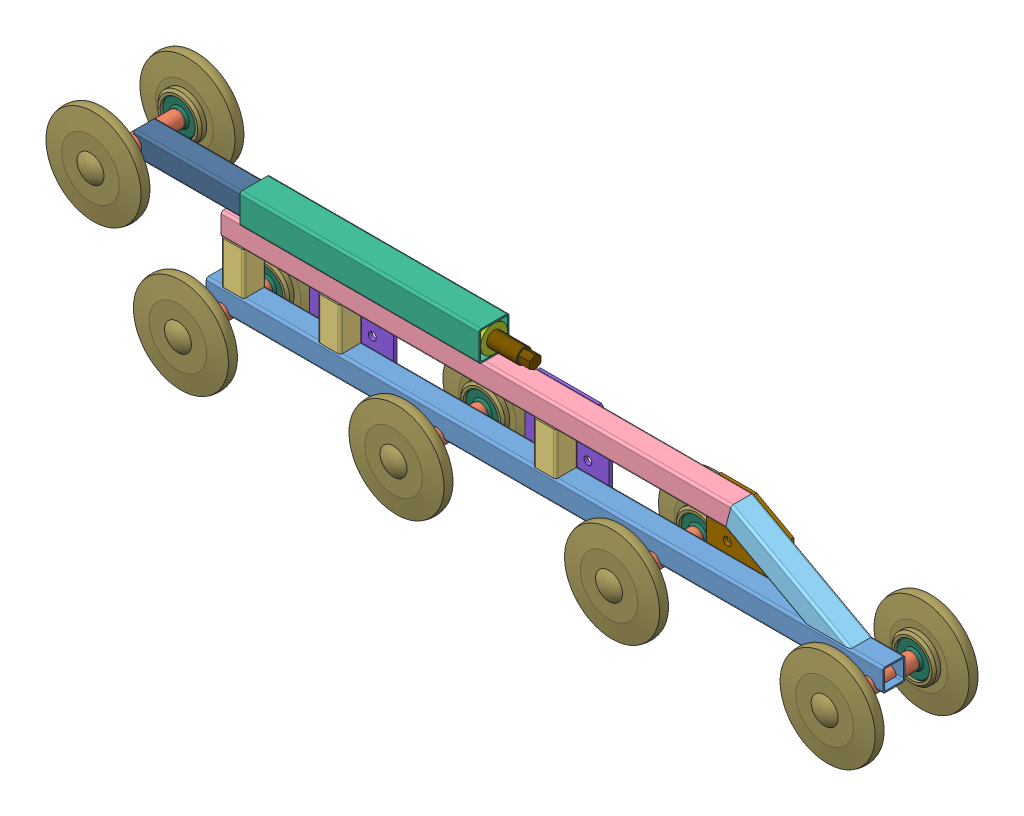
SolidWorks assembly ТП.016.02.00 - Гусеничный модуль в сборе, configuration Левый. Lengths in mm.
Overall size (1147.02 302.71 157.68).
97 component instances, 18 part files, 54 mates.
Components (placement in the parent):
- ТП.016.02.01.00 - Модуль гусеницы силовой-1: ТП.016.02.01.00 - Модуль гусеницы силовой [Левый] at origin size (904.98 176.07 133.68)
  - ТП.016.02.01.01.00 - Рама гусеницы с осями-1: ТП.016.02.01.01.00 - Рама гусеницы с осями [00] at origin size (904.98 176.07 133.68)
    - ТП.016.02.01.01.01 - Нижняя балка гуленицы (30х30)-1: ТП.016.02.01.01.01 - Нижняя балка гуленицы (30х30) [--] at origin size (904.98 30 30)
    - ТП.016.02.01.01.02(02) - Ось цельная 21_3мм-1: ТП.016.02.01.01.02(02) - Ось цельная 21_3мм [--] x (0 0 1) z (-1 0 0) size (133.68 21.3 21.3)
    - ТП.016.02.01.01.02(02) - Ось цельная 21_3мм-2: ТП.016.02.01.01.02(02) - Ось цельная 21_3мм [--] at (288.3267 0 0) x (0 0 1) z (-0.987351 0.158553 0) size (133.68 21.3 21.3)
    - ТП.016.02.01.01.02(02) - Ось цельная 21_3мм-3: ТП.016.02.01.01.02(02) - Ось цельная 21_3мм [--] at (576.6534 0 0) x (0 0 1) z (-0.959125 0.282984 0) size (133.68 21.3 21.3)
    - ТП.016.02.01.01.02(02) - Ось цельная 21_3мм-4: ТП.016.02.01.01.02(02) - Ось цельная 21_3мм [--] at (864.9801 0 0) x (0 0 1) z (-0.928571 0.371154 0) size (133.68 21.3 21.3)
    - ТП.016.02.01.01.03 - Связка балок гусеничного модуля-1: ТП.016.02.01.01.03 - Связка балок гусеничного модуля [--] at (0 86.7738 0) x (-1 0 0) z (0 0 -1) size (30 56.77 30)
    - ТП.016.02.01.01.03 - Связка балок гусеничного модуля-2: ТП.016.02.01.01.03 - Связка балок гусеничного модуля [--] at (129.1634 86.7738 0) x (-1 0 0) z (0 0 -1) size (30 56.77 30)
    - ТП.016.02.01.01.03 - Связка балок гусеничного модуля-3: ТП.016.02.01.01.03 - Связка балок гусеничного модуля [--] at (417.4901 86.7738 0) x (-1 0 0) z (0 0 -1) size (30 56.77 30)
    - ТП.016.02.01.01.04 - Верхняя балка рамы гусеницы-1: ТП.016.02.01.01.04 - Верхняя балка рамы гусеницы [--] at (0 136.7738 0) x (0 0 1) z (-1 0 0) size (30 129.94 872.16)
    - ТП.016.02.01.01.05 - Задняя косая-1: ТП.016.02.01.01.05 - Задняя косая [--] at (864.9801 0 -15) x (0 0 -1) z (0.877984 -0.478691 0) size (30 30 181.27)
    - ТП.016.02.01.01.06.00 - Стакан натяжителя-1: ТП.016.02.01.01.06.00 - Стакан натяжителя [00] at (30 136.7738 0) x (-1 0 0) z (0 0 -1) size (320 50.91 50.91)
      - ТП.016.02.01.01.06.01 - Рубашка штока ролика натяжного-1: ТП.016.02.01.01.06.01 - Рубашка штока ролика натяжного [--] at origin size (320 40 40)
      - ТП.016.02.01.01.06.02 - Гайка рубашки штока-1: ТП.016.02.01.01.06.02 - Гайка рубашки штока [--] at (-320 0 0) x (0 -0.713098 -0.701064) z (1 0 0) size (36 36 20)
  - ТП.016.01.01.01.01.02 - Пластина кронштейна (5мм)-1: ТП.016.01.01.01.01.02 - Пластина кронштейна (5мм) [--] at (144.1634 0 20) size (112 110.77 5) (hidden)
  - ТП.016.01.01.01.01.02 - Пластина кронштейна (5мм)-2: ТП.016.01.01.01.01.02 - Пластина кронштейна (5мм) [--] at (432.4901 0 20) size (112 110.77 5) (hidden)
  - ТП.016.01.01.01.01.05 - Пластина кронштейна задняя (5мм)-1: ТП.016.01.01.01.01.05 - Пластина кронштейна задняя (5мм) [--] at (674.9034 0 15) x (-1 0 0) z (0 0 -1) size (112 110.77 5) (hidden)
  - ТП.016.01.01.01.01.02 - Пластина кронштейна (5мм)-4: ТП.016.01.01.01.01.02 - Пластина кронштейна (5мм) [--] at (144.1634 0 -20) x (-1 0 0) z (0 0 -1) size (112 110.77 5)
  - ТП.016.01.01.01.01.02 - Пластина кронштейна (5мм)-6: ТП.016.01.01.01.01.02 - Пластина кронштейна (5мм) [--] at (432.4901 0 -20) x (-1 0 0) z (0 0 -1) size (112 110.77 5)
  - ТП.016.01.01.01.01.05 - Пластина кронштейна задняя (5мм)-2: ТП.016.01.01.01.01.05 - Пластина кронштейна задняя (5мм) [--] at (674.9034 0 -20) x (-1 0 0) z (0 0 -1) size (112 110.77 5)
- ТП.016.02.02.00 - Натяжитель гусеницы-1: ТП.016.02.02.00 - Натяжитель гусеницы [00] at (-117 136.7738 0) x (-1 0 0) z (0 0 1) size (371.74 149.44 157.68)
  - ТП.016.02.02.01.00 - Толкатель натяжки-1: ТП.016.02.02.01.00 - Толкатель натяжки [00] at origin size (311.12 30 133.68)
    - ТП.016.02.02.01.01 - Шток натяжного ролика (30х30)-1: ТП.016.02.02.01.01 - Шток натяжного ролика (30х30) [--] at origin size (297.02 30 30)
    - ТП.016.02.01.01.02(02) - Ось цельная 21_3мм-1: ТП.016.02.01.01.02(02) - Ось цельная 21_3мм [--] x (0 0 1) z (-0.910058 0.41448 0) size (133.68 21.3 21.3)
    - ТП.016.02.02.01.02 - Заглушка штока-1: ТП.016.02.02.01.02 - Заглушка штока [--] at (-297.0168 0 0) x (0 -1 0) z (1 0 0) size (26 26 20)
  - Каток 129(47) в сборе-1: Каток 129(47) в сборе [00] at (0 0 62.8416) x (0 0 1) z (1 0 0) size (35.7 129 129)
    - Каток 129(47)-1: Каток 129(47) [--] at origin size (35 129 129)
    - Подшипник ГОСТ 8338-75 -1: Подшипник ГОСТ 8338-75  [Подшипник 204 ГОСТ 8338-75] at (-1 0 0) x (1 0 0) z (0 -0.327433 -0.944874) size (14 47 47)
    - Стопор внутренний до 165мм (ГОСТ 13943-86)-1: Стопор внутренний до 165мм (ГОСТ 13943-86) [Кольцо 47] at (-8 0 0) x (0 0.910839 0.412761) z (-1 0 0) size (49.5 51.2 1.7)
    - Сальник 47х20-1: Сальник 47х20 [--] at (-9.7 0 0) x (-1 0 0) z (0 0.937697 -0.347453) size (10 47 47)
  - Каток 129(47) в сборе-2: Каток 129(47) в сборе [00] at (0 0 -62.8416) x (0 0 -1) z (-0.173648 0.984808 0) size (35.7 129 129)
    - Каток 129(47)-1: Каток 129(47) [--] at origin size (35 129 129)
    - Подшипник ГОСТ 8338-75 -1: Подшипник ГОСТ 8338-75  [Подшипник 204 ГОСТ 8338-75] at (-1 0 0) x (1 0 0) z (0 -0.327433 -0.944874) size (14 47 47)
    - Стопор внутренний до 165мм (ГОСТ 13943-86)-1: Стопор внутренний до 165мм (ГОСТ 13943-86) [Кольцо 47] at (-8 0 0) x (0 0.910839 0.412761) z (-1 0 0) size (49.5 51.2 1.7)
    - Сальник 47х20-1: Сальник 47х20 [--] at (-9.7 0 0) x (-1 0 0) z (0 0.937697 -0.347453) size (10 47 47)
  - ТП.016.02.02.02 - Шайба оси-1: ТП.016.02.02.02 - Шайба оси [--] at (0 0 -66.3614) x (0 0 1) z (0.48394 0.875101 0) size (4 24 24)
  - Болты с шестигранной головкой кт.В (ГОСТ 7798-70)-1: Болты с шестигранной головкой кт.В (ГОСТ 7798-70) [Болт М6-6gx14(S10) ГОСТ 7798-77] at (0 0 -69.3416) x (0 0 1) z (0.143998 -0.989578 0) size (18 10.9 10)
  - ТП.016.02.02.02 - Шайба оси-2: ТП.016.02.02.02 - Шайба оси [--] at (0 0 66.3614) x (0 0 -1) z (0.777771 0.628548 0) size (4 24 24)
  - Болты с шестигранной головкой кт.В (ГОСТ 7798-70)-2: Болты с шестигранной головкой кт.В (ГОСТ 7798-70) [Болт М6-6gx14(S10) ГОСТ 7798-77] at (0 0 69.3416) x (0 0 -1) z (-0.999549 -0.030028 0) size (18 10.9 10)
- ТП.016.02.03 - Винт натяжителя-1: ТП.016.02.03 - Винт натяжителя [--] at (350.0168 136.7738 0) x (0 -0.01927 -0.999814) z (-1 0 0) size (20 20 231.35)
- Каток 129(47) в сборе-1: Каток 129(47) в сборе [00] at (0 0 -62.8416) x (0 0 -1) z (-0.261474 0.96521 0) size (35.7 129 129)
  - Каток 129(47)-1: Каток 129(47) [--] at origin size (35 129 129)
  - Подшипник ГОСТ 8338-75 -1: Подшипник ГОСТ 8338-75  [Подшипник 204 ГОСТ 8338-75] at (-1 0 0) x (1 0 0) z (0 -0.327433 -0.944874) size (14 47 47)
  - Стопор внутренний до 165мм (ГОСТ 13943-86)-1: Стопор внутренний до 165мм (ГОСТ 13943-86) [Кольцо 47] at (-8 0 0) x (0 0.910839 0.412761) z (-1 0 0) size (49.5 51.2 1.7)
  - Сальник 47х20-1: Сальник 47х20 [--] at (-9.7 0 0) x (-1 0 0) z (0 0.937697 -0.347453) size (10 47 47)
- Каток 129(47) в сборе-2: Каток 129(47) в сборе [00] at (288.3267 0 -62.8416) x (0 0 -1) z (-0.411203 0.911544 0) size (35.7 129 129)
  - Каток 129(47)-1: Каток 129(47) [--] at origin size (35 129 129)
  - Подшипник ГОСТ 8338-75 -1: Подшипник ГОСТ 8338-75  [Подшипник 204 ГОСТ 8338-75] at (-1 0 0) x (1 0 0) z (0 -0.327433 -0.944874) size (14 47 47)
  - Стопор внутренний до 165мм (ГОСТ 13943-86)-1: Стопор внутренний до 165мм (ГОСТ 13943-86) [Кольцо 47] at (-8 0 0) x (0 0.910839 0.412761) z (-1 0 0) size (49.5 51.2 1.7)
  - Сальник 47х20-1: Сальник 47х20 [--] at (-9.7 0 0) x (-1 0 0) z (0 0.937697 -0.347453) size (10 47 47)
- Каток 129(47) в сборе-4: Каток 129(47) в сборе [00] at (576.6534 0 -62.8416) x (0 0 -1) z (-0.523925 0.851764 0) size (35.7 129 129)
  - Каток 129(47)-1: Каток 129(47) [--] at origin size (35 129 129)
  - Подшипник ГОСТ 8338-75 -1: Подшипник ГОСТ 8338-75  [Подшипник 204 ГОСТ 8338-75] at (-1 0 0) x (1 0 0) z (0 -0.327433 -0.944874) size (14 47 47)
  - Стопор внутренний до 165мм (ГОСТ 13943-86)-1: Стопор внутренний до 165мм (ГОСТ 13943-86) [Кольцо 47] at (-8 0 0) x (0 0.910839 0.412761) z (-1 0 0) size (49.5 51.2 1.7)
  - Сальник 47х20-1: Сальник 47х20 [--] at (-9.7 0 0) x (-1 0 0) z (0 0.937697 -0.347453) size (10 47 47)
- Каток 129(47) в сборе-6: Каток 129(47) в сборе [00] at (864.9801 0 -62.8416) x (0 0 -1) z (0.601039 -0.79922 0) size (35.7 129 129)
  - Каток 129(47)-1: Каток 129(47) [--] at origin size (35 129 129)
  - Подшипник ГОСТ 8338-75 -1: Подшипник ГОСТ 8338-75  [Подшипник 204 ГОСТ 8338-75] at (-1 0 0) x (1 0 0) z (0 -0.327433 -0.944874) size (14 47 47)
  - Стопор внутренний до 165мм (ГОСТ 13943-86)-1: Стопор внутренний до 165мм (ГОСТ 13943-86) [Кольцо 47] at (-8 0 0) x (0 0.910839 0.412761) z (-1 0 0) size (49.5 51.2 1.7)
  - Сальник 47х20-1: Сальник 47х20 [--] at (-9.7 0 0) x (-1 0 0) z (0 0.937697 -0.347453) size (10 47 47)
- Каток 129(47) в сборе-8: Каток 129(47) в сборе [00] at (864.9801 0 62.8416) x (0 0 1) z (0.907466 0.420125 0) size (35.7 129 129)
  - Каток 129(47)-1: Каток 129(47) [--] at origin size (35 129 129)
  - Подшипник ГОСТ 8338-75 -1: Подшипник ГОСТ 8338-75  [Подшипник 204 ГОСТ 8338-75] at (-1 0 0) x (1 0 0) z (0 -0.327433 -0.944874) size (14 47 47)
  - Стопор внутренний до 165мм (ГОСТ 13943-86)-1: Стопор внутренний до 165мм (ГОСТ 13943-86) [Кольцо 47] at (-8 0 0) x (0 0.910839 0.412761) z (-1 0 0) size (49.5 51.2 1.7)
  - Сальник 47х20-1: Сальник 47х20 [--] at (-9.7 0 0) x (-1 0 0) z (0 0.937697 -0.347453) size (10 47 47)
- Каток 129(47) в сборе-10: Каток 129(47) в сборе [00] at (576.6534 0 62.8416) x (0 0 1) z (0.820726 0.571322 0) size (35.7 129 129)
  - Каток 129(47)-1: Каток 129(47) [--] at origin size (35 129 129)
  - Подшипник ГОСТ 8338-75 -1: Подшипник ГОСТ 8338-75  [Подшипник 204 ГОСТ 8338-75] at (-1 0 0) x (1 0 0) z (0 -0.327433 -0.944874) size (14 47 47)
  - Стопор внутренний до 165мм (ГОСТ 13943-86)-1: Стопор внутренний до 165мм (ГОСТ 13943-86) [Кольцо 47] at (-8 0 0) x (0 0.910839 0.412761) z (-1 0 0) size (49.5 51.2 1.7)
  - Сальник 47х20-1: Сальник 47х20 [--] at (-9.7 0 0) x (-1 0 0) z (0 0.937697 -0.347453) size (10 47 47)
- Каток 129(47) в сборе-12: Каток 129(47) в сборе [00] at (288.3267 0 62.8416) x (0 0 1) z (0.709048 0.70516 0) size (35.7 129 129)
  - Каток 129(47)-1: Каток 129(47) [--] at origin size (35 129 129)
  - Подшипник ГОСТ 8338-75 -1: Подшипник ГОСТ 8338-75  [Подшипник 204 ГОСТ 8338-75] at (-1 0 0) x (1 0 0) z (0 -0.327433 -0.944874) size (14 47 47)
  - Стопор внутренний до 165мм (ГОСТ 13943-86)-1: Стопор внутренний до 165мм (ГОСТ 13943-86) [Кольцо 47] at (-8 0 0) x (0 0.910839 0.412761) z (-1 0 0) size (49.5 51.2 1.7)
  - Сальник 47х20-1: Сальник 47х20 [--] at (-9.7 0 0) x (-1 0 0) z (0 0.937697 -0.347453) size (10 47 47)
- Каток 129(47) в сборе-14: Каток 129(47) в сборе [00] at (0 0 62.8416) x (0 0 1) z (0.575827 0.817572 0) size (35.7 129 129)
  - Каток 129(47)-1: Каток 129(47) [--] at origin size (35 129 129)
  - Подшипник ГОСТ 8338-75 -1: Подшипник ГОСТ 8338-75  [Подшипник 204 ГОСТ 8338-75] at (-1 0 0) x (1 0 0) z (0 -0.327433 -0.944874) size (14 47 47)
  - Стопор внутренний до 165мм (ГОСТ 13943-86)-1: Стопор внутренний до 165мм (ГОСТ 13943-86) [Кольцо 47] at (-8 0 0) x (0 0.910839 0.412761) z (-1 0 0) size (49.5 51.2 1.7)
  - Сальник 47х20-1: Сальник 47х20 [--] at (-9.7 0 0) x (-1 0 0) z (0 0.937697 -0.347453) size (10 47 47)
- ТП.016.02.02.02 - Шайба оси-1: ТП.016.02.02.02 - Шайба оси [--] at (0 0 -66.3614) x (0 0 1) z (0.502694 0.864464 0) size (4 24 24)
- Болты с шестигранной головкой кт.В (ГОСТ 7798-70)-1: Болты с шестигранной головкой кт.В (ГОСТ 7798-70) [Болт М6-6gx16(S10) ГОСТ 7798-77] at (0 0 -69.3416) x (0 0 1) z (0.899536 0.436848 0) size (20 10.9 10)
- ТП.016.02.02.02 - Шайба оси-2: ТП.016.02.02.02 - Шайба оси [--] at (288.3267 0 -66.3614) x (0 0 1) z (0.359272 0.933233 0) size (4 24 24)
- Болты с шестигранной головкой кт.В (ГОСТ 7798-70)-2: Болты с шестигранной головкой кт.В (ГОСТ 7798-70) [Болт М6-6gx16(S10) ГОСТ 7798-77] at (288.3267 0 -69.3416) x (0 0 1) z (0.818894 0.573945 0) size (20 10.9 10)
- ТП.016.02.02.02 - Шайба оси-4: ТП.016.02.02.02 - Шайба оси [--] at (576.6534 0 -66.3614) x (0 0 1) z (0.237517 0.971383 0) size (4 24 24)
- Болты с шестигранной головкой кт.В (ГОСТ 7798-70)-4: Болты с шестигранной головкой кт.В (ГОСТ 7798-70) [Болт М6-6gx16(S10) ГОСТ 7798-77] at (576.6534 0 -69.3416) x (0 0 1) z (0.739146 0.673545 0) size (20 10.9 10)
- ТП.016.02.02.02 - Шайба оси-6: ТП.016.02.02.02 - Шайба оси [--] at (864.9801 0 -66.3614) x (0 0 1) z (0.145939 0.989294 0) size (4 24 24)
- Болты с шестигранной головкой кт.В (ГОСТ 7798-70)-6: Болты с шестигранной головкой кт.В (ГОСТ 7798-70) [Болт М6-6gx16(S10) ГОСТ 7798-77] at (864.9801 0 -69.3416) x (0 0 1) z (0.673145 0.73951 0) size (20 10.9 10)
- ТП.016.02.02.02 - Шайба оси-8: ТП.016.02.02.02 - Шайба оси [--] at (864.9801 0 66.3614) x (0 0 -1) z (0.339092 0.940753 0) size (4 24 24)
- Болты с шестигранной головкой кт.В (ГОСТ 7798-70)-8: Болты с шестигранной головкой кт.В (ГОСТ 7798-70) [Болт М6-6gx16(S10) ГОСТ 7798-77] at (864.9801 0 69.3416) x (0 0 -1) z (-0.243566 0.969884 0) size (20 10.9 10)
- ТП.016.02.02.02 - Шайба оси-11: ТП.016.02.02.02 - Шайба оси [--] at (576.6534 0 66.3614) x (0 0 -1) z (0.170581 0.985344 0) size (4 24 24)
- Болты с шестигранной головкой кт.В (ГОСТ 7798-70)-11: Болты с шестигранной головкой кт.В (ГОСТ 7798-70) [Болт М6-6gx16(S10) ГОСТ 7798-77] at (576.6534 0 69.3416) x (0 0 -1) z (-0.408284 0.912855 0) size (20 10.9 10)
- ТП.016.02.02.02 - Шайба оси-13: ТП.016.02.02.02 - Шайба оси [--] at (288.3267 0 66.3614) x (0 0 -1) z (-0.003114 0.999995 0) size (4 24 24)
- Болты с шестигранной головкой кт.В (ГОСТ 7798-70)-13: Болты с шестигранной головкой кт.В (ГОСТ 7798-70) [Болт М6-6gx16(S10) ГОСТ 7798-77] at (288.3267 0 69.3416) x (0 0 -1) z (-0.560597 0.828089 0) size (20 10.9 10)
- ТП.016.02.02.02 - Шайба оси-15: ТП.016.02.02.02 - Шайба оси [--] at (0 0 66.3614) x (0 0 -1) z (-0.176714 0.984262 0) size (4 24 24)
- Болты с шестигранной головкой кт.В (ГОСТ 7798-70)-15: Болты с шестигранной головкой кт.В (ГОСТ 7798-70) [Болт М6-6gx16(S10) ГОСТ 7798-77] at (0 0 69.3416) x (0 0 -1) z (-0.695876 0.718162 0) size (20 10.9 10)
Mates (geometry in assembly coordinates):
- Расстояние1: distance = 147 mm: point of ТП.016.02.02.00 - Натяжитель гусеницы-1/ТП.016.02.02.01.00 - Толкатель натяжки-1/ТП.016.02.02.01.01 - Шток натяжного ролика (30х30)-1; plane of ТП.016.02.01.00 - Модуль гусеницы силовой-1/ТП.016.02.01.01.00 - Рама гусеницы с осями-1/ТП.016.02.01.01.06.00 - Стакан натяжителя-1/ТП.016.02.01.01.06.01 - Рубашка штока ролика натяжного-1 through (30 119.7738 -17) normal (-1 0 0)
- Параллельность1: parallel: plane of ТП.016.02.01.00 - Модуль гусеницы силовой-1/ТП.016.02.01.01.00 - Рама гусеницы с осями-1/ТП.016.02.01.01.06.00 - Стакан натяжителя-1/ТП.016.02.01.01.06.01 - Рубашка штока ролика натяжного-1 through (350 153.7738 20) normal (0 0 1); plane of ТП.016.02.02.00 - Натяжитель гусеницы-1/ТП.016.02.02.01.00 - Толкатель натяжки-1/ТП.016.02.02.01.01 - Шток натяжного ролика (30х30)-1 through (402.4432 124.7738 15) normal (0 0 1)
- Симметричный1: symmetric: plane of ТП.016.02.02.00 - Натяжитель гусеницы-1/ТП.016.02.02.01.00 - Толкатель натяжки-1/ТП.016.02.02.01.01 - Шток натяжного ролика (30х30)-1 through (402.4432 124.7738 -15) normal (0 0 -1); plane of ТП.016.02.02.00 - Натяжитель гусеницы-1/ТП.016.02.02.01.00 - Толкатель натяжки-1/ТП.016.02.02.01.01 - Шток натяжного ролика (30х30)-1 through (402.4432 124.7738 15) normal (0 0 1); plane of assembly
- Параллельность2: parallel: plane of ТП.016.02.01.00 - Модуль гусеницы силовой-1/ТП.016.02.01.01.00 - Рама гусеницы с осями-1/ТП.016.02.01.01.06.00 - Стакан натяжителя-1/ТП.016.02.01.01.06.01 - Рубашка штока ролика натяжного-1 through (350 118.7738 -16) normal (0 1 0); plane of ТП.016.02.02.00 - Натяжитель гусеницы-1/ТП.016.02.02.01.00 - Толкатель натяжки-1/ТП.016.02.02.01.01 - Шток натяжного ролика (30х30)-1 through (402.4432 121.7738 12) normal (0 -1 0)
- Концентричный1: concentric: cylinder of ТП.016.02.01.00 - Модуль гусеницы силовой-1/ТП.016.02.01.01.00 - Рама гусеницы с осями-1/ТП.016.02.01.01.06.00 - Стакан натяжителя-1/ТП.016.02.01.01.06.02 - Гайка рубашки штока-1 through (350 136.7738 0) axis (1 0 0) radius 8.75; cylinder of ТП.016.02.03 - Винт натяжителя-1 through (-406.564 136.7738 0) axis (-1 0 0) radius 10
- Совпадение2: coincident: point of ТП.016.02.02.00 - Натяжитель гусеницы-1/ТП.016.02.02.01.00 - Толкатель натяжки-1/ТП.016.02.02.01.02 - Заглушка штока-1; point of ТП.016.02.03 - Винт натяжителя-1
- Концентричный2: concentric: cylinder of Каток 129(47) в сборе-1/Подшипник ГОСТ 8338-75 -1 through (0 0 938.1584) axis (0 0 1) radius 10; cylinder of ТП.016.02.01.00 - Модуль гусеницы силовой-1/ТП.016.02.01.01.00 - Рама гусеницы с осями-1/ТП.016.02.01.01.02(02) - Ось цельная 21_3мм-1 through (0 0 -66.8416) axis (0 0 -1) radius 10.65
- Расстояние2: distance = 2 mm: plane of Каток 129(47) в сборе-1/Подшипник ГОСТ 8338-75 -1 through (9.5035 6.4757 -68.8416) normal (0 0 -1); plane of ТП.016.02.01.00 - Модуль гусеницы силовой-1/ТП.016.02.01.01.00 - Рама гусеницы с осями-1/ТП.016.02.01.01.02(02) - Ось цельная 21_3мм-1 through (0 0 -66.8416) normal (0 0 -1)
- Концентричный3: concentric: cylinder of Каток 129(47) в сборе-2/Подшипник ГОСТ 8338-75 -1 through (288.3267 0 938.1584) axis (0 0 1) radius 10; cylinder of ТП.016.02.01.00 - Модуль гусеницы силовой-1/ТП.016.02.01.01.00 - Рама гусеницы с осями-1/ТП.016.02.01.01.02(02) - Ось цельная 21_3мм-2 through (288.3267 0 -66.8416) axis (0 0 -1) radius 10
- Расстояние3: distance = 2 mm: plane of Каток 129(47) в сборе-2/Подшипник ГОСТ 8338-75 -1 through (296.6832 7.9006 -68.8416) normal (0 0 -1); plane of ТП.016.02.01.00 - Модуль гусеницы силовой-1/ТП.016.02.01.01.00 - Рама гусеницы с осями-1/ТП.016.02.01.01.02(02) - Ось цельная 21_3мм-2 through (288.3267 0 -66.8416) normal (0 0 -1)
- Концентричный4: concentric: cylinder of ТП.016.02.01.00 - Модуль гусеницы силовой-1/ТП.016.02.01.01.00 - Рама гусеницы с осями-1/ТП.016.02.01.01.02(02) - Ось цельная 21_3мм-3 through (576.6534 0 -66.8416) axis (0 0 -1) radius 10; cylinder of Каток 129(47) в сборе-4/Подшипник ГОСТ 8338-75 -1 through (576.6534 0 938.1584) axis (0 0 1) radius 10
- Расстояние4: distance = 2 mm: plane of Каток 129(47) в сборе-4/Подшипник ГОСТ 8338-75 -1 through (583.9359 8.9003 -68.8416) normal (0 0 -1); plane of ТП.016.02.01.00 - Модуль гусеницы силовой-1/ТП.016.02.01.01.00 - Рама гусеницы с осями-1/ТП.016.02.01.01.02(02) - Ось цельная 21_3мм-3 through (576.6534 0 -66.8416) normal (0 0 -1)
- Концентричный5: concentric: cylinder of ТП.016.02.01.00 - Модуль гусеницы силовой-1/ТП.016.02.01.01.00 - Рама гусеницы с осями-1/ТП.016.02.01.01.02(02) - Ось цельная 21_3мм-4 through (864.9801 0 -66.8416) axis (0 0 -1) radius 10; cylinder of Каток 129(47) в сборе-6/Подшипник ГОСТ 8338-75 -1 through (864.9801 0 938.1584) axis (0 0 1) radius 10
- Расстояние5: distance = 2 mm: plane of Каток 129(47) в сборе-6/Подшипник ГОСТ 8338-75 -1 through (858.559 -9.5404 -68.8416) normal (0 0 -1); plane of ТП.016.02.01.00 - Модуль гусеницы силовой-1/ТП.016.02.01.01.00 - Рама гусеницы с осями-1/ТП.016.02.01.01.02(02) - Ось цельная 21_3мм-4 through (864.9801 0 -66.8416) normal (0 0 -1)
- Концентричный6: concentric: cylinder of ТП.016.02.01.00 - Модуль гусеницы силовой-1/ТП.016.02.01.01.00 - Рама гусеницы с осями-1/ТП.016.02.01.01.02(02) - Ось цельная 21_3мм-4 through (864.9801 0 66.8416) axis (0 0 1) radius 10; cylinder of Каток 129(47) в сборе-8/Подшипник ГОСТ 8338-75 -1 through (864.9801 0 -938.1584) axis (0 0 -1) radius 10
- Расстояние6: distance = 2 mm: plane of Каток 129(47) в сборе-8/Подшипник ГОСТ 8338-75 -1 through (863.8321 11.4426 68.8416) normal (0 0 1); plane of ТП.016.02.01.00 - Модуль гусеницы силовой-1/ТП.016.02.01.01.00 - Рама гусеницы с осями-1/ТП.016.02.01.01.02(02) - Ось цельная 21_3мм-4 through (864.9801 0 66.8416) normal (0 0 1)
- Концентричный7: concentric: cylinder of ТП.016.02.01.00 - Модуль гусеницы силовой-1/ТП.016.02.01.01.00 - Рама гусеницы с осями-1/ТП.016.02.01.01.02(02) - Ось цельная 21_3мм-3 through (576.6534 0 66.8416) axis (0 0 1) radius 10; cylinder of Каток 129(47) в сборе-10/Подшипник ГОСТ 8338-75 -1 through (576.6534 0 -938.1584) axis (0 0 -1) radius 10; plane of ?
- Расстояние7: distance = 2 mm: plane of Каток 129(47) в сборе-10/Подшипник ГОСТ 8338-75 -1 through (573.5358 11.0694 68.8416) normal (0 0 1); plane of ?; plane of ТП.016.02.01.00 - Модуль гусеницы силовой-1/ТП.016.02.01.01.00 - Рама гусеницы с осями-1/ТП.016.02.01.01.02(02) - Ось цельная 21_3мм-3 through (576.6534 0 66.8416) normal (0 0 1)
- Концентричный8: concentric: cylinder of ТП.016.02.01.00 - Модуль гусеницы силовой-1/ТП.016.02.01.01.00 - Рама гусеницы с осями-1/ТП.016.02.01.01.02(02) - Ось цельная 21_3мм-2 through (288.3267 0 66.8416) axis (0 0 1) radius 10; cylinder of Каток 129(47) в сборе-12/Подшипник ГОСТ 8338-75 -1 through (288.3267 0 -938.1584) axis (0 0 -1) radius 10
- Расстояние8: distance = 2 mm: plane of Каток 129(47) в сборе-12/Подшипник ГОСТ 8338-75 -1 through (283.3343 10.3598 68.8416) normal (0 0 1); plane of ТП.016.02.01.00 - Модуль гусеницы силовой-1/ТП.016.02.01.01.00 - Рама гусеницы с осями-1/ТП.016.02.01.01.02(02) - Ось цельная 21_3мм-2 through (288.3267 0 66.8416) normal (0 0 1)
- Концентричный9: concentric: cylinder of ТП.016.02.01.00 - Модуль гусеницы силовой-1/ТП.016.02.01.01.00 - Рама гусеницы с осями-1/ТП.016.02.01.01.02(02) - Ось цельная 21_3мм-1 through (0 0 66.8416) axis (0 0 1) radius 10; cylinder of Каток 129(47) в сборе-14/Подшипник ГОСТ 8338-75 -1 through (0 0 -938.1584) axis (0 0 -1) radius 10
- Расстояние9: distance = 2 mm: plane of Каток 129(47) в сборе-14/Подшипник ГОСТ 8338-75 -1 through (-6.7155 9.3355 68.8416) normal (0 0 1); plane of ТП.016.02.01.00 - Модуль гусеницы силовой-1/ТП.016.02.01.01.00 - Рама гусеницы с осями-1/ТП.016.02.01.01.02(02) - Ось цельная 21_3мм-1 through (0 0 66.8416) normal (0 0 1)
- Совпадение3: coincident: plane of Каток 129(47) в сборе-1/Подшипник ГОСТ 8338-75 -1 through (9.5035 6.4757 -68.8416) normal (0 0 -1); plane of ТП.016.02.02.02 - Шайба оси-1 through (10.3736 -6.0323 -68.8416) normal (0 0 1)
- Концентричный10: concentric: cylinder of Каток 129(47) в сборе-1/Подшипник ГОСТ 8338-75 -1 through (0 0 938.1584) axis (0 0 1) radius 10; cylinder of ТП.016.02.02.02 - Шайба оси-1 through (0 0 -70.8416) axis (0 0 -1) radius 10
- Совпадение4: coincident: plane of ТП.016.02.02.02 - Шайба оси-1 through (7.3479 -4.2729 -69.3416) normal (0 0 -1); plane of Болты с шестигранной головкой кт.В (ГОСТ 7798-70)-1 through (2.3808 -4.9025 -69.3416) normal (0 0 1)
- Концентричный11: concentric: cylinder of Болты с шестигранной головкой кт.В (ГОСТ 7798-70)-1 through (0 0 -1069.3416) axis (0 0 -1) radius 3; cylinder of ТП.016.02.02.02 - Шайба оси-1 through (0 0 -70.8416) axis (0 0 -1) radius 3.25
- Совпадение5: coincident: plane of ТП.016.02.02.02 - Шайба оси-2 through (296.2592 -3.0538 -69.3416) normal (0 0 -1); plane of Болты с шестигранной головкой кт.В (ГОСТ 7798-70)-2 through (291.4547 -4.463 -69.3416) normal (0 0 1)
- Концентричный12: concentric: cylinder of ТП.016.02.02.02 - Шайба оси-2 through (288.3267 0 -70.8416) axis (0 0 -1) radius 3.25; cylinder of Болты с шестигранной головкой кт.В (ГОСТ 7798-70)-2 through (288.3267 0 -1069.3416) axis (0 0 -1) radius 3
- Совпадение6: coincident: plane of Каток 129(47) в сборе-2/Подшипник ГОСТ 8338-75 -1 through (296.6832 7.9006 -68.8416) normal (0 0 -1); plane of ТП.016.02.02.02 - Шайба оси-2 through (299.5255 -4.3113 -68.8416) normal (0 0 1)
- Концентричный13: concentric: cylinder of Каток 129(47) в сборе-2/Подшипник ГОСТ 8338-75 -1 through (288.3267 0 938.1584) axis (0 0 1) radius 10; cylinder of ТП.016.02.02.02 - Шайба оси-2 through (288.3267 0 -70.8416) axis (0 0 -1) radius 10
- Совпадение8: coincident: plane of ТП.016.02.02.02 - Шайба оси-4 through (584.9102 -2.0189 -69.3416) normal (0 0 -1); plane of Болты с шестигранной головкой кт.В (ГОСТ 7798-70)-4 through (580.3242 -4.0283 -69.3416) normal (0 0 1)
- Концентричный15: concentric: cylinder of ТП.016.02.02.02 - Шайба оси-4 through (576.6534 0 -70.8416) axis (0 0 -1) radius 3.25; cylinder of Болты с шестигранной головкой кт.В (ГОСТ 7798-70)-4 through (576.6534 0 -1069.3416) axis (0 0 -1) radius 3
- Совпадение9: coincident: plane of Каток 129(47) в сборе-4/Подшипник ГОСТ 8338-75 -1 through (583.9359 8.9003 -68.8416) normal (0 0 -1); plane of ТП.016.02.02.02 - Шайба оси-4 through (588.31 -2.8502 -68.8416) normal (0 0 1)
- Концентричный16: concentric: cylinder of Каток 129(47) в сборе-4/Подшипник ГОСТ 8338-75 -1 through (576.6534 0 938.1584) axis (0 0 1) radius 10; cylinder of ТП.016.02.02.02 - Шайба оси-4 through (576.6534 0 -70.8416) axis (0 0 -1) radius 10
- Совпадение11: coincident: plane of ТП.016.02.02.02 - Шайба оси-6 through (873.3891 -1.2405 -69.3416) normal (0 0 -1); plane of Болты с шестигранной головкой кт.В (ГОСТ 7798-70)-6 through (869.0104 -3.6686 -69.3416) normal (0 0 1)
- Концентричный18: concentric: cylinder of ТП.016.02.02.02 - Шайба оси-6 through (864.9801 0 -70.8416) axis (0 0 -1) radius 3.25; cylinder of Болты с шестигранной головкой кт.В (ГОСТ 7798-70)-6 through (864.9801 0 -1069.3416) axis (0 0 -1) radius 3
- Совпадение12: coincident: plane of Каток 129(47) в сборе-6/Подшипник ГОСТ 8338-75 -1 through (858.559 -9.5404 -68.8416) normal (0 0 -1); plane of ТП.016.02.02.02 - Шайба оси-6 through (876.8516 -1.7513 -68.8416) normal (0 0 1)
- Концентричный19: concentric: cylinder of Каток 129(47) в сборе-6/Подшипник ГОСТ 8338-75 -1 through (864.9801 0 938.1584) axis (0 0 1) radius 10; cylinder of ТП.016.02.02.02 - Шайба оси-6 through (864.9801 0 -70.8416) axis (0 0 -1) radius 10
- Совпадение14: coincident: plane of ТП.016.02.02.02 - Шайба оси-8 through (856.9837 2.8823 69.3416) normal (0 0 1); plane of Болты с шестигранной головкой кт.В (ГОСТ 7798-70)-8 through (859.6942 -1.3274 69.3416) normal (0 0 -1)
- Концентричный21: concentric: cylinder of ТП.016.02.02.02 - Шайба оси-8 through (864.9801 0 70.8416) axis (0 0 1) radius 3.25; cylinder of Болты с шестигранной головкой кт.В (ГОСТ 7798-70)-8 through (864.9801 0 1069.3416) axis (0 0 1) radius 3
- Совпадение15: coincident: plane of Каток 129(47) в сборе-8/Подшипник ГОСТ 8338-75 -1 through (863.8321 11.4426 68.8416) normal (0 0 1); plane of ТП.016.02.02.02 - Шайба оси-8 through (853.6911 4.0691 68.8416) normal (0 0 -1)
- Концентричный22: concentric: cylinder of Каток 129(47) в сборе-8/Подшипник ГОСТ 8338-75 -1 through (864.9801 0 -938.1584) axis (0 0 -1) radius 10; cylinder of ТП.016.02.02.02 - Шайба оси-8 through (864.9801 0 70.8416) axis (0 0 1) radius 10
- Совпадение19: coincident: plane of ТП.016.02.02.02 - Шайба оси-11 through (568.278 1.4499 69.3416) normal (0 0 1); plane of Болты с шестигранной головкой кт.В (ГОСТ 7798-70)-11 through (571.6784 -2.2251 69.3416) normal (0 0 -1)
- Концентричный25: concentric: cylinder of ТП.016.02.02.02 - Шайба оси-11 through (576.6534 0 70.8416) axis (0 0 1) radius 3.25; cylinder of Болты с шестигранной головкой кт.В (ГОСТ 7798-70)-11 through (576.6534 0 1069.3416) axis (0 0 1) radius 3
- Совпадение20: coincident: plane of Каток 129(47) в сборе-10/Подшипник ГОСТ 8338-75 -1 through (573.5358 11.0694 68.8416) normal (0 0 1); plane of ?; plane of ТП.016.02.02.02 - Шайба оси-11 through (564.8293 2.047 68.8416) normal (0 0 -1)
- Концентричный26: concentric: cylinder of Каток 129(47) в сборе-10/Подшипник ГОСТ 8338-75 -1 through (576.6534 0 -938.1584) axis (0 0 -1) radius 10; plane of ?; cylinder of ТП.016.02.02.02 - Шайба оси-11 through (576.6534 0 70.8416) axis (0 0 1) radius 10
- Совпадение22: coincident: plane of ТП.016.02.02.02 - Шайба оси-13 through (279.8267 -0.0265 69.3416) normal (0 0 1); plane of Болты с шестигранной головкой кт.В (ГОСТ 7798-70)-13 through (283.8136 -3.0553 69.3416) normal (0 0 -1)
- Концентричный28: concentric: cylinder of ТП.016.02.02.02 - Шайба оси-13 through (288.3267 0 70.8416) axis (0 0 1) radius 3.25; cylinder of Болты с шестигранной головкой кт.В (ГОСТ 7798-70)-13 through (288.3267 0 1069.3416) axis (0 0 1) radius 3
- Совпадение23: coincident: plane of Каток 129(47) в сборе-12/Подшипник ГОСТ 8338-75 -1 through (283.3343 10.3598 68.8416) normal (0 0 1); plane of ТП.016.02.02.02 - Шайба оси-13 through (276.3268 -0.0374 68.8416) normal (0 0 -1)
- Концентричный29: concentric: cylinder of Каток 129(47) в сборе-12/Подшипник ГОСТ 8338-75 -1 through (288.3267 0 -938.1584) axis (0 0 -1) radius 10; cylinder of ТП.016.02.02.02 - Шайба оси-13 through (288.3267 0 70.8416) axis (0 0 1) radius 10
- Совпадение25: coincident: plane of ТП.016.02.02.02 - Шайба оси-15 through (-8.3662 -1.5021 69.3416) normal (0 0 1); plane of Болты с шестигранной головкой кт.В (ГОСТ 7798-70)-15 through (-3.914 -3.7925 69.3416) normal (0 0 -1)
- Концентричный31: concentric: cylinder of ТП.016.02.02.02 - Шайба оси-15 through (0 0 70.8416) axis (0 0 1) radius 3.25; cylinder of Болты с шестигранной головкой кт.В (ГОСТ 7798-70)-15 through (0 0 1069.3416) axis (0 0 1) radius 3
- Совпадение26: coincident: plane of Каток 129(47) в сборе-14/Подшипник ГОСТ 8338-75 -1 through (-6.7155 9.3355 68.8416) normal (0 0 1); plane of ТП.016.02.02.02 - Шайба оси-15 through (-11.8111 -2.1206 68.8416) normal (0 0 -1)
- Концентричный32: concentric: cylinder of Каток 129(47) в сборе-14/Подшипник ГОСТ 8338-75 -1 through (0 0 -938.1584) axis (0 0 -1) radius 10; cylinder of ТП.016.02.02.02 - Шайба оси-15 through (0 0 70.8416) axis (0 0 1) radius 10
